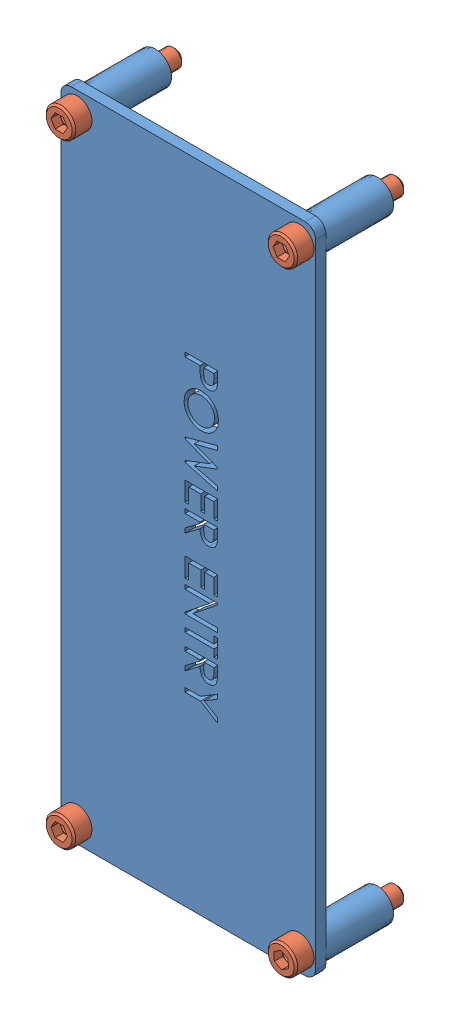
SolidWorks assembly PowerInputTerminals, configuration Default. Lengths in mm.
Overall size (50.33 127.17 22.56).
5 component instances, 2 part files, 8 mates.
Components (placement in the parent):
- InTermPCB-1: InTermPCB [Default] at origin size (49.53 127 15.19)
- socket head cap screw_ai-1: socket head cap screw_ai [HX-SHCS 0.138-32x0.75x0.75-N] at (176.2653 -139.8361 5.5118) x (0 0 -1) z (0 1 0) size (22.56 5.74 5.74)
- socket head cap screw_ai-2: socket head cap screw_ai [HX-SHCS 0.138-32x0.75x0.75-N] at (176.2653 -20.4561 5.5118) x (0 0 -1) z (0 1 0) size (22.56 5.74 5.74)
- socket head cap screw_ai-3: socket head cap screw_ai [HX-SHCS 0.138-32x0.75x0.75-N] at (219.4453 -139.8361 5.5118) x (0 0 -1) z (-0.549805 0.835293 0) size (22.56 5.74 5.74)
- socket head cap screw_ai-4: socket head cap screw_ai [HX-SHCS 0.138-32x0.75x0.75-N] at (219.4453 -20.4561 5.5118) x (0 0 -1) z (0 1 0) size (22.56 5.74 5.74)
Mates (geometry in assembly coordinates):
- Concentric6: concentric aligned: cylinder of InTermPCB-1 through (176.2653 -139.8361 -128.4162) axis (0 0 1) radius 1.3526; cylinder of socket head cap screw_ai-1 through (176.2653 -139.8361 37.2618) axis (0 0 1) radius 2.8702
- Concentric10: concentric aligned: cylinder of InTermPCB-1 through (176.2653 -20.4561 -22.1629) axis (0 0 1) radius 3.175; cylinder of socket head cap screw_ai-2 through (176.2653 -20.4561 37.2618) axis (0 0 1) radius 1.7526
- Concentric11: concentric aligned: cylinder of InTermPCB-1 through (219.4453 -20.4561 -22.1629) axis (0 0 1) radius 3.175; cylinder of socket head cap screw_ai-4 through (219.4453 -20.4561 37.2618) axis (0 0 1) radius 1.7526
- Concentric12: concentric aligned: cylinder of InTermPCB-1 through (219.4453 -139.8361 -22.1629) axis (0 0 1) radius 3.175; cylinder of socket head cap screw_ai-3 through (219.4453 -139.8361 37.2618) axis (0 0 1) radius 1.7526
- Coincident6: coincident aligned: plane of socket head cap screw_ai-1 through (176.2653 -139.8361 5.5118) normal (0 0 1); plane of socket head cap screw_ai-3 through (219.4453 -139.8361 5.5118) normal (0 0 1)
- Coincident7: coincident aligned: plane of socket head cap screw_ai-3 through (219.4453 -139.8361 5.5118) normal (0 0 1); plane of socket head cap screw_ai-4 through (219.4453 -20.4561 5.5118) normal (0 0 1)
- Coincident8: coincident aligned: plane of socket head cap screw_ai-2 through (176.2653 -20.4561 5.5118) normal (0 0 1); plane of socket head cap screw_ai-4 through (219.4453 -20.4561 5.5118) normal (0 0 1)
- Coincident9: coincident anti-aligned: plane of InTermPCB-1 through (222.6203 -143.6461 2.0066) normal (0 0 1); plane of socket head cap screw_ai-4 through (216.5751 -20.4561 2.0066) normal (0 0 -1)
